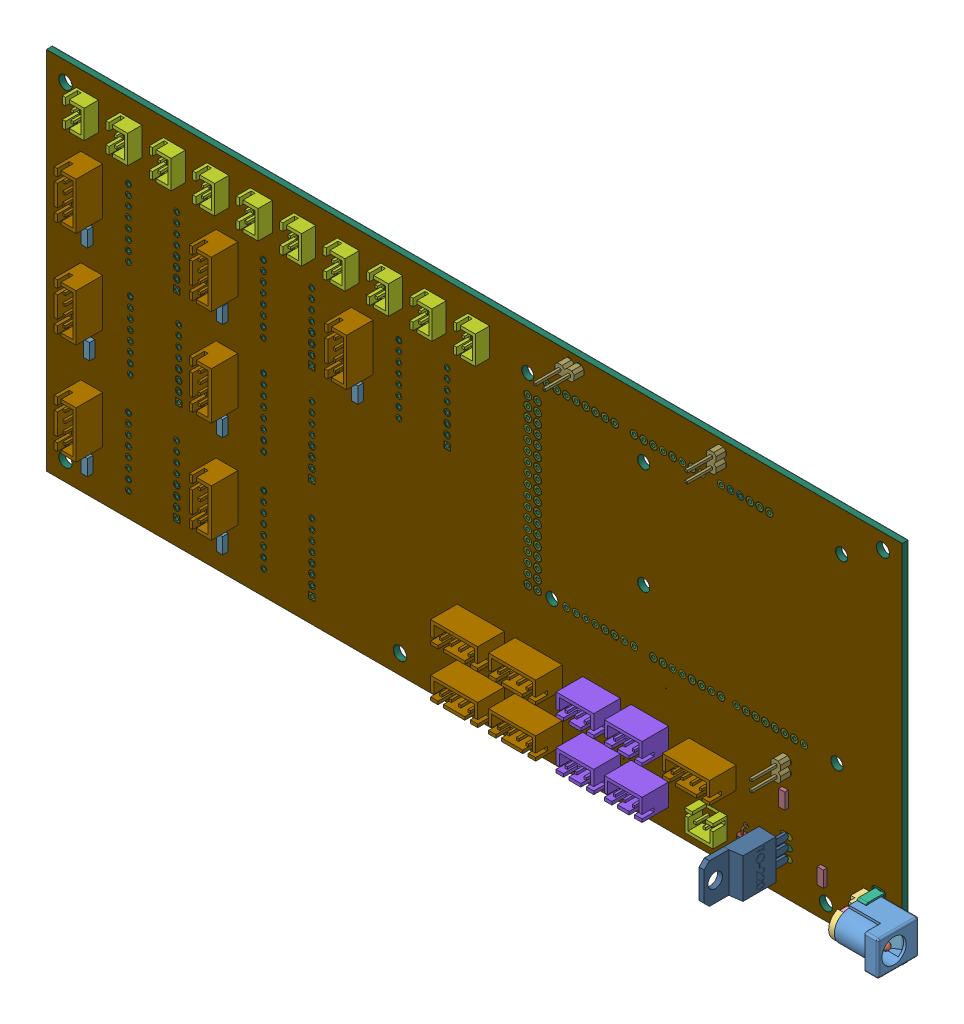
SolidWorks assembly pcb v1, configuration Predeterminado. Lengths in mm.
Overall size (229.58 96 28.88).
82 component instances, 19 part files, 0 mates.
Components (placement in the parent):
- pcb v1.step-1: pcb v1.step [Predeterminado] at origin size (229.58 96 28.88)
  - Packages.step-1: Packages.step [Predeterminado] at origin size (221.63 90.79 28.88)
    - 694106301002.step-1: 694106301002.step [Predeterminado] at (229.526 8.89 1.5525) x (-1 0 0) z (0 0 1) size (14.5 9.5 14.5)
      - 6941xx301002.step-1: 6941xx301002.step [Predeterminado] at (3.4425 0.008 5.5) x (0 -1 0) z (0 0 1) size (9 11.8 10.7)
      - 694106301002_PinContact.step-1: 694106301002_PinContact.step [Predeterminado] at (7.4425 0.008 6.65) x (0 -1 0) z (0 0 1) size (3.2 12.8 3.2)
      - 6941xx301002_Back.step-1: 6941xx301002_Back.step [Predeterminado] at (12.5425 0.008 3.4) x (0 -1 0) z (0 0 1) size (7.6 6.55 10.3)
      - 6941xx301002_PinContact2.step-1: 6941xx301002_PinContact2.step [Predeterminado] at (13.7425 0.008 6.65) x (0 -1 0) z (0 0 1) size (5 1.8 12.4)
      - 6941xx301002_PinLame.step-1: 6941xx301002_PinLame.step [Predeterminado] at (7.6925 0.008 1.15) x (0 -1 0) z (0 0 1) size (6.95 10.6 8.97)
      - 6941xx301002_PinBis.step-1: 6941xx301002_PinBis.step [Predeterminado] at (10.5425 -0.567 4.15) x (0 1 0) z (0 0 1) size (8.45 3.55 8.2)
    - B2B-XH-A.step-1: B2B-XH-A.step [Predeterminado] at (11.43 88.9 1.5525) x (0 -1 0) z (0 0 1) size (7.4 5.75 10.4)
      - B2B-XH-A v1.step-1: B2B-XH-A v1.step [Predeterminado] at (1.25 -0.6024 -3.2628) x (1 0 0) z (0 -1 0) size (7.4 10.4 5.75)
    - B2B-XH-A.step-2: B2B-XH-A.step [Predeterminado] at (22.86 88.9 1.5525) x (0 -1 0) z (0 0 1) size (7.4 5.75 10.4)
      - B2B-XH-A v1.step-1: B2B-XH-A v1.step [Predeterminado] at (1.25 -0.6024 -3.2628) x (1 0 0) z (0 -1 0) size (7.4 10.4 5.75)
    - B2B-XH-A.step-3: B2B-XH-A.step [Predeterminado] at (34.29 88.9 1.5525) x (0 -1 0) z (0 0 1) size (7.4 5.75 10.4)
      - B2B-XH-A v1.step-1: B2B-XH-A v1.step [Predeterminado] at (1.25 -0.6024 -3.2628) x (1 0 0) z (0 -1 0) size (7.4 10.4 5.75)
    - B2B-XH-A.step-4: B2B-XH-A.step [Predeterminado] at (45.72 88.9 1.5525) x (0 -1 0) z (0 0 1) size (7.4 5.75 10.4)
      - B2B-XH-A v1.step-1: B2B-XH-A v1.step [Predeterminado] at (1.25 -0.6024 -3.2628) x (1 0 0) z (0 -1 0) size (7.4 10.4 5.75)
    - B2B-XH-A.step-5: B2B-XH-A.step [Predeterminado] at (57.15 88.9 1.5525) x (0 -1 0) z (0 0 1) size (7.4 5.75 10.4)
      - B2B-XH-A v1.step-1: B2B-XH-A v1.step [Predeterminado] at (1.25 -0.6024 -3.2628) x (1 0 0) z (0 -1 0) size (7.4 10.4 5.75)
    - B2B-XH-A.step-6: B2B-XH-A.step [Predeterminado] at (68.58 88.9 1.5525) x (0 -1 0) z (0 0 1) size (7.4 5.75 10.4)
      - B2B-XH-A v1.step-1: B2B-XH-A v1.step [Predeterminado] at (1.25 -0.6024 -3.2628) x (1 0 0) z (0 -1 0) size (7.4 10.4 5.75)
    - B2B-XH-A.step-7: B2B-XH-A.step [Predeterminado] at (80.01 88.9 1.5525) x (0 -1 0) z (0 0 1) size (7.4 5.75 10.4)
      - B2B-XH-A v1.step-1: B2B-XH-A v1.step [Predeterminado] at (1.25 -0.6024 -3.2628) x (1 0 0) z (0 -1 0) size (7.4 10.4 5.75)
    - B2B-XH-A.step-8: B2B-XH-A.step [Predeterminado] at (91.44 88.9 1.5525) x (0 -1 0) z (0 0 1) size (7.4 5.75 10.4)
      - B2B-XH-A v1.step-1: B2B-XH-A v1.step [Predeterminado] at (1.25 -0.6024 -3.2628) x (1 0 0) z (0 -1 0) size (7.4 10.4 5.75)
    - B2B-XH-A.step-9: B2B-XH-A.step [Predeterminado] at (102.87 88.9 1.5525) x (0 -1 0) z (0 0 1) size (7.4 5.75 10.4)
      - B2B-XH-A v1.step-1: B2B-XH-A v1.step [Predeterminado] at (1.25 -0.6024 -3.2628) x (1 0 0) z (0 -1 0) size (7.4 10.4 5.75)
    - B2B-XH-A.step-10: B2B-XH-A.step [Predeterminado] at (114.3 88.9 1.5525) x (0 -1 0) z (0 0 1) size (7.4 5.75 10.4)
      - B2B-XH-A v1.step-1: B2B-XH-A v1.step [Predeterminado] at (1.25 -0.6024 -3.2628) x (1 0 0) z (0 -1 0) size (7.4 10.4 5.75)
    - B2B-XH-A.step-11: B2B-XH-A.step [Predeterminado] at (176.6 7.6 1.5525) x (-1 0 0) z (0 0 1) size (7.4 5.75 10.4)
      - B2B-XH-A v1.step-1: B2B-XH-A v1.step [Predeterminado] at (1.25 -0.6024 -3.2628) x (1 0 0) z (0 -1 0) size (7.4 10.4 5.75)
    - B3B-XH-A.step-1: B3B-XH-A.step [Predeterminado] at (156.21 7.62 1.5525) size (9.9 5.75 10.4)
      - B3B-XH-A v1.step-1: B3B-XH-A v1.step [Predeterminado] at (2.5 0.5458 0.003) x (1 0 0) z (0 -1 0) size (9.9 10.4 5.75)
    - B3B-XH-A.step-2: B3B-XH-A.step [Predeterminado] at (156.21 20.32 1.5525) size (9.9 5.75 10.4)
      - B3B-XH-A v1.step-1: B3B-XH-A v1.step [Predeterminado] at (2.5 0.5458 0.003) x (1 0 0) z (0 -1 0) size (9.9 10.4 5.75)
    - B3B-XH-A.step-3: B3B-XH-A.step [Predeterminado] at (143.51 7.62 1.5525) size (9.9 5.75 10.4)
      - B3B-XH-A v1.step-1: B3B-XH-A v1.step [Predeterminado] at (2.5 0.5458 0.003) x (1 0 0) z (0 -1 0) size (9.9 10.4 5.75)
    - B3B-XH-A.step-4: B3B-XH-A.step [Predeterminado] at (143.51 20.32 1.5525) size (9.9 5.75 10.4)
      - B3B-XH-A v1.step-1: B3B-XH-A v1.step [Predeterminado] at (2.5 0.5458 0.003) x (1 0 0) z (0 -1 0) size (9.9 10.4 5.75)
    - B4B-XH-A.step-1: B4B-XH-A.step [Predeterminado] at (82.55 74.93 1.5525) x (0 -1 0) z (0 0 1) size (12.4 5.75 10.4)
      - B4B-XH-A v1.step-1: B4B-XH-A v1.step [Predeterminado] at (3.75 0.5275 0.0013) x (1 0 0) z (0 -1 0) size (12.4 10.4 5.75)
    - B4B-XH-A.step-2: B4B-XH-A.step [Predeterminado] at (46.99 22.86 1.5525) x (0 -1 0) z (0 0 1) size (12.4 5.75 10.4)
      - B4B-XH-A v1.step-1: B4B-XH-A v1.step [Predeterminado] at (3.75 0.5275 0.0013) x (1 0 0) z (0 -1 0) size (12.4 10.4 5.75)
    - B4B-XH-A.step-3: B4B-XH-A.step [Predeterminado] at (46.99 74.93 1.5525) x (0 -1 0) z (0 0 1) size (12.4 5.75 10.4)
      - B4B-XH-A v1.step-1: B4B-XH-A v1.step [Predeterminado] at (3.75 0.5275 0.0013) x (1 0 0) z (0 -1 0) size (12.4 10.4 5.75)
    - B4B-XH-A.step-4: B4B-XH-A.step [Predeterminado] at (11.43 74.93 1.5525) x (0 -1 0) z (0 0 1) size (12.4 5.75 10.4)
      - B4B-XH-A v1.step-1: B4B-XH-A v1.step [Predeterminado] at (3.75 0.5275 0.0013) x (1 0 0) z (0 -1 0) size (12.4 10.4 5.75)
    - B4B-XH-A.step-5: B4B-XH-A.step [Predeterminado] at (11.43 49.53 1.5525) x (0 -1 0) z (0 0 1) size (12.4 5.75 10.4)
      - B4B-XH-A v1.step-1: B4B-XH-A v1.step [Predeterminado] at (3.75 0.5275 0.0013) x (1 0 0) z (0 -1 0) size (12.4 10.4 5.75)
    - B4B-XH-A.step-6: B4B-XH-A.step [Predeterminado] at (11.43 22.86 1.5525) x (0 -1 0) z (0 0 1) size (12.4 5.75 10.4)
      - B4B-XH-A v1.step-1: B4B-XH-A v1.step [Predeterminado] at (3.75 0.5275 0.0013) x (1 0 0) z (0 -1 0) size (12.4 10.4 5.75)
    - B4B-XH-A.step-7: B4B-XH-A.step [Predeterminado] at (46.99 49.53 1.5525) x (0 -1 0) z (0 0 1) size (12.4 5.75 10.4)
      - B4B-XH-A v1.step-1: B4B-XH-A v1.step [Predeterminado] at (3.75 0.5275 0.0013) x (1 0 0) z (0 -1 0) size (12.4 10.4 5.75)
    - B4B-XH-A.step-8: B4B-XH-A.step [Predeterminado] at (110.49 20.32 1.5525) size (12.4 5.75 10.4)
      - B4B-XH-A v1.step-1: B4B-XH-A v1.step [Predeterminado] at (3.75 0.5275 0.0013) x (1 0 0) z (0 -1 0) size (12.4 10.4 5.75)
    - B4B-XH-A.step-9: B4B-XH-A.step [Predeterminado] at (110.49 7.62 1.5525) size (12.4 5.75 10.4)
      - B4B-XH-A v1.step-1: B4B-XH-A v1.step [Predeterminado] at (3.75 0.5275 0.0013) x (1 0 0) z (0 -1 0) size (12.4 10.4 5.75)
    - B4B-XH-A.step-10: B4B-XH-A.step [Predeterminado] at (125.73 20.32 1.5525) size (12.4 5.75 10.4)
      - B4B-XH-A v1.step-1: B4B-XH-A v1.step [Predeterminado] at (3.75 0.5275 0.0013) x (1 0 0) z (0 -1 0) size (12.4 10.4 5.75)
    - B4B-XH-A.step-11: B4B-XH-A.step [Predeterminado] at (125.73 7.62 1.5525) size (12.4 5.75 10.4)
      - B4B-XH-A v1.step-1: B4B-XH-A v1.step [Predeterminado] at (3.75 0.5275 0.0013) x (1 0 0) z (0 -1 0) size (12.4 10.4 5.75)
    - B4B-XH-A.step-12: B4B-XH-A.step [Predeterminado] at (171.45 20.32 1.5525) size (12.4 5.75 10.4)
      - B4B-XH-A v1.step-1: B4B-XH-A v1.step [Predeterminado] at (3.75 0.5275 0.0013) x (1 0 0) z (0 -1 0) size (12.4 10.4 5.75)
    - TO220V.step-1: TO220V.step [Predeterminado] at (192.1013 11.7613 1.5525) x (0 1 0) z (0 0 1) size (10.39 4.6 28.88)
    - RESAD724W46L381D178B.step-1: RESAD724W46L381D178B.step [Predeterminado] at (184 7.6 1.5525) x (0 1 0) z (0 0 1) size (7.7 2.03 3.95)
    - 1X02.step-1: 1X02.step [Predeterminado] at (194.4 30.2 1.5525) x (0 1 0) z (0 0 1) size (5.08 2.54 12.64)
    - 1X02.step-2: 1X02.step [Predeterminado] at (177.4 92 1.5525) x (0 -1 0) z (0 0 1) size (5.08 2.54 12.64)
    - 1X02.step-3: 1X02.step [Predeterminado] at (138.8 93.152 1.5525) x (-1 0 0) z (0 0 1) size (5.08 2.54 12.64)
    - CPOL-RADIAL-2.5MM-5MM.step-1: CPOL-RADIAL-2.5MM-5MM.step [Predeterminado] at (204.47 10.16 1.5525) x (0 -1 0) z (0 0 1) size (4.15 1.65 0.94)
    - CPOL-RADIAL-2.5MM-5MM.step-2: CPOL-RADIAL-2.5MM-5MM.step [Predeterminado] at (194.31 22.86 1.5525) x (0 1 0) z (0 0 1) size (4.15 1.65 0.94)
    - CPOL-RADIAL-2.5MM-6.5MM.step-1: CPOL-RADIAL-2.5MM-6.5MM.step [Predeterminado] at (82.55 59.69 1.5525) x (0 -1 0) z (0 0 1) size (4.15 1.65 1.44)
    - CPOL-RADIAL-2.5MM-6.5MM.step-2: CPOL-RADIAL-2.5MM-6.5MM.step [Predeterminado] at (46.99 60.09 1.5525) x (0 -1 0) z (0 0 1) size (4.15 1.65 1.44)
    - CPOL-RADIAL-2.5MM-6.5MM.step-3: CPOL-RADIAL-2.5MM-6.5MM.step [Predeterminado] at (46.99 34.29 1.5525) x (0 -1 0) z (0 0 1) size (4.15 1.65 1.44)
    - CPOL-RADIAL-2.5MM-6.5MM.step-4: CPOL-RADIAL-2.5MM-6.5MM.step [Predeterminado] at (46.99 7.62 1.5525) x (0 -1 0) z (0 0 1) size (4.15 1.65 1.44)
    - CPOL-RADIAL-2.5MM-6.5MM.step-5: CPOL-RADIAL-2.5MM-6.5MM.step [Predeterminado] at (11.43 59.69 1.5525) x (0 -1 0) z (0 0 1) size (4.15 1.65 1.44)
    - CPOL-RADIAL-2.5MM-6.5MM.step-6: CPOL-RADIAL-2.5MM-6.5MM.step [Predeterminado] at (11.9815 34.29 1.5525) x (0 -1 0) z (0 0 1) size (4.15 1.65 1.44)
    - CPOL-RADIAL-2.5MM-6.5MM.step-7: CPOL-RADIAL-2.5MM-6.5MM.step [Predeterminado] at (11.43 7.62 1.5525) x (0 -1 0) z (0 0 1) size (4.15 1.65 1.44)
  - Board.step-1: Board.step [Predeterminado] at origin size (225 96 1.5)
  - 1-copper.step-1: 1-copper.step [Predeterminado] at (0 0 1.5) size (212.13 93.05 0.03)
  - 16-copper.step-1: 16-copper.step [Predeterminado] at (0 0 -0.035) size (222.97 93.97 0.03)
  - 1-soldermask.step-1: 1-soldermask.step [Predeterminado] at (0 0 1.5) size (225 96 0.05)
  - 16-soldermask.step-1: 16-soldermask.step [Predeterminado] at origin size (225 96 0.05)
